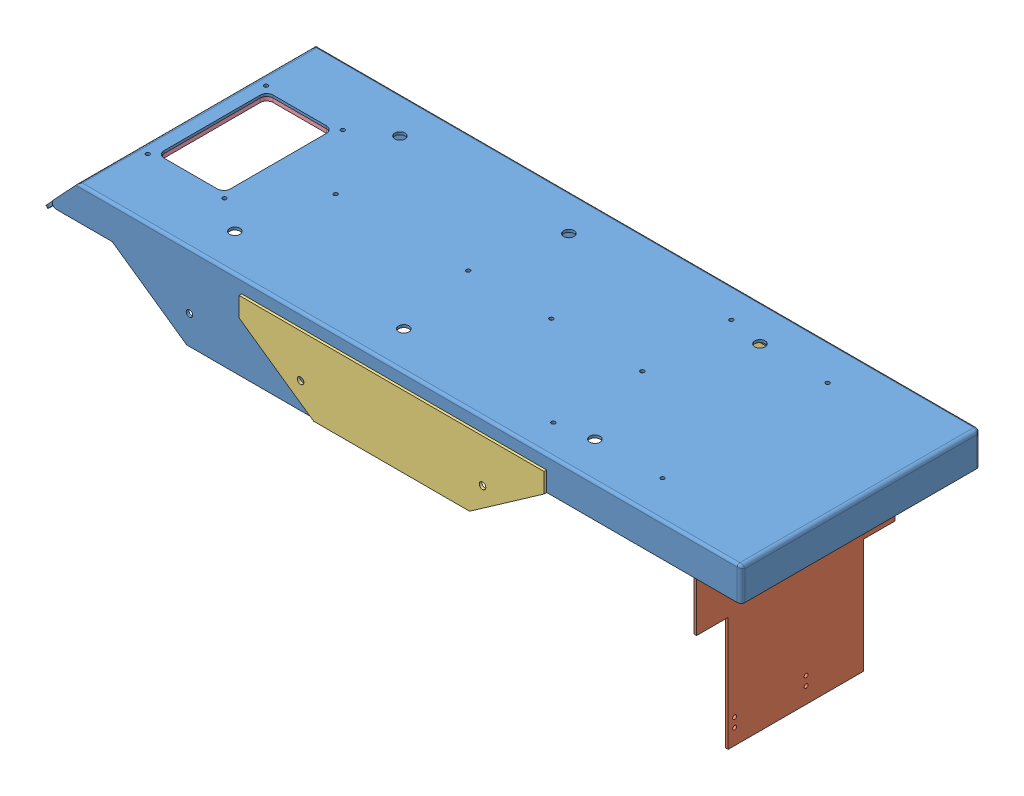
SolidWorks assembly Fairing, configuration Default. Lengths in mm.
Overall size (540.69 167 188).
5 component instances, 4 part files, 9 mates.
Components (placement in the parent):
- Fairing-1: Fairing [Default] at origin size (540.69 65.75 184)
- Rear_support-1: Rear_support [Default] at (-30 0 0) size (49 165 152.5)
- Side_cover-1: Side_cover [Default] at (0 0 0) size (234.68 55.15 2)
- Side_cover-2: Side_cover [Default] at (0 0 -186) size (234.68 55.15 2)
- Rod_support-1: Rod_support [Default] at origin size (72 7.54 100)
Mates (geometry in assembly coordinates):
- Concentric1: concentric anti-aligned: cylinder of Fairing-1 through (421 2 63.5) axis (0 -1 0) radius 1.5; cylinder of Rear_support-1 through (421 -2 63.5) axis (0 1 0) radius 1.5
- Concentric2: concentric anti-aligned: cylinder of Fairing-1 through (421 2 -63.5) axis (0 -1 0) radius 1.5; cylinder of Rear_support-1 through (421 -2 -63.5) axis (0 1 0) radius 1.5
- Coincident1: coincident anti-aligned: plane of Fairing-1 through (0 0 0) normal (0 -1 0); plane of Rear_support-1 through (-30 0 0) normal (0 1 0)
- Coincident2: coincident anti-aligned: plane of Fairing-1 through (0 2 92) normal (0 0 1); plane of Side_cover-1 through (0 0 92) normal (0 0 -1)
- Coincident3: coincident aligned: plane of Fairing-1 through (83.4707 -63.7477 90) normal (0 -1 0); plane of Side_cover-1 through (0 -63.7477 94) normal (0 -1 0)
- Coincident6: coincident aligned: plane of Side_cover-1 through (0 -63.7477 94) normal (0 -1 0); plane of Side_cover-2 through (0 -63.7477 -92) normal (0 -1 0)
- Coincident7: coincident anti-aligned: plane of Fairing-1 through (0 2 -92) normal (0 0 -1); plane of Side_cover-2 through (0 0 -92) normal (0 0 1)
- Coincident8: coincident aligned: plane of Side_cover-1 through (360.4057 0 102) normal (1 0 0); plane of Side_cover-2 through (360.4057 0 -84) normal (1 0 0)
- Distance1: distance = 186 mm: point of Side_cover-2
